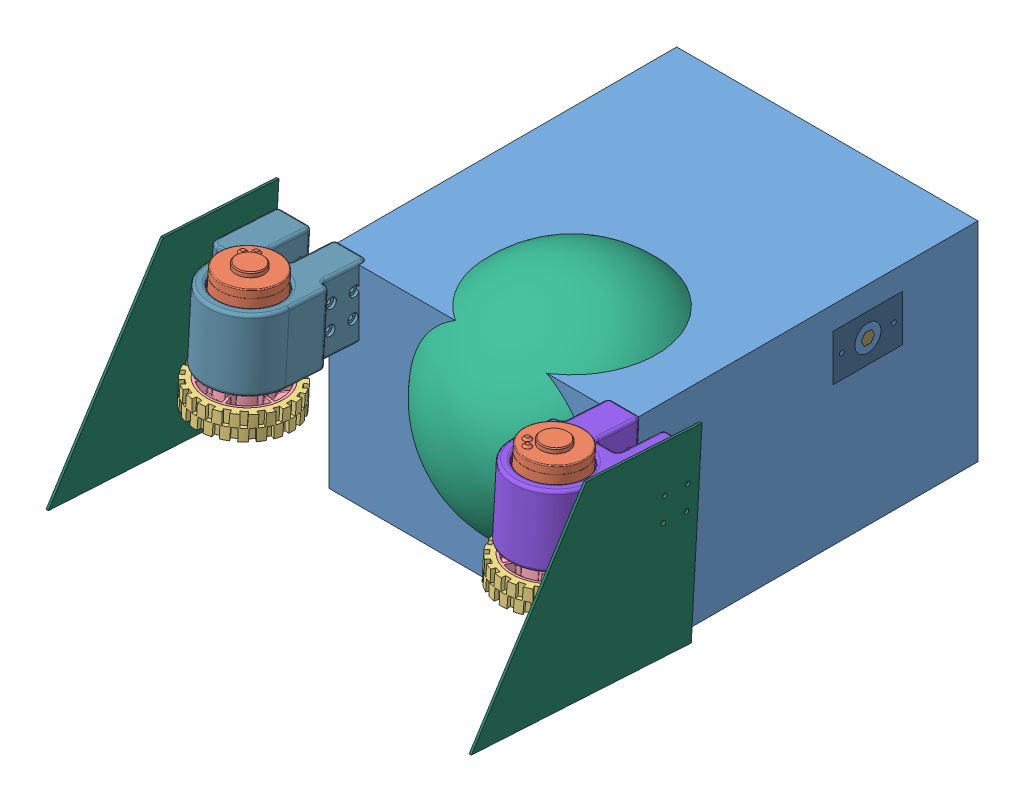
SolidWorks assembly shooter v2, configuration Default. Lengths in mm.
Overall size (466.79 413.55 625.13).
118 component instances, 42 part files, 85 mates.
Components (placement in the parent):
- shooter boundry-1: shooter boundry [Default] at origin size (330.2 228.6 381)
- MiniCIM Motor-1: MiniCIM Motor [Default] at (-2.032 166.4532 471.1566) x (0 0.998301 -0.058266) z (0 0.058266 0.998301) size (133.06 64.01 64.01)
- 4 in HiGrip Wheel-1: 4 in HiGrip Wheel [Default] at (1.2293 143.8954 473.9437) x (0 0.998301 -0.058266) z (-0.935788 0.020542 0.351965) size (35.12 101.6 101.6)
  - 4 in tread-1: 4 in tread [Default] at (-8.0517 2.5236 2.5343) size (25.4 101.6 101.6)
  - 4in 2013 Hub-1: 4in 2013 Hub [Default] at (-8.0517 2.5236 2.5343) size (35.12 82.55 82.55)
- am-0320a_8mm_Key_Hub-1: am-0320a_8mm_Key_Hub [Default] at (-2.032 158.6564 471.6117) x (0.162565 -0.05749 -0.985022) z (0 -0.998301 0.058266) size (57.15 57.15 25.4)
- am-0320a_8mm_Key_Hub-2: am-0320a_8mm_Key_Hub [Default] at (332.232 158.6564 471.6117) x (-0.795747 0.035287 0.6046) z (0 -0.998301 0.058266) size (57.15 57.15 25.4)
- 4 in HiGrip Wheel-2: 4 in HiGrip Wheel [Default] at (330.8694 143.6172 469.1771) x (0 0.998301 -0.058266) z (0.922364 0.022509 0.385666) size (35.12 101.6 101.6)
  - 4 in tread-1: 4 in tread [Default] at (-8.0517 2.5236 2.5343) size (25.4 101.6 101.6)
  - 4in 2013 Hub-1: 4in 2013 Hub [Default] at (-8.0517 2.5236 2.5343) size (35.12 82.55 82.55)
- MiniCIM Motor-2: MiniCIM Motor [Default] at (332.232 166.4532 471.1566) x (0 0.998301 -0.058266) z (1 0 0) size (133.06 64.01 64.01)
- ball-1: ball [Default] at (188.4903 141.6409 303.234) x (0.677862 -0.6998 0.22535) z (-0.733706 -0.663389 0.146935) size (254 254 254)
- shooter bar-1: shooter bar [Default] at (317.5 150.9632 96.7731) x (0 0.058266 0.998301) z (-1 0 0) size (330.2 50.8 4.06)
- shooter bar-2: shooter bar [Default] at (16.764 150.9632 96.7731) x (0 0.058266 0.998301) z (-1 0 0) size (330.2 50.8 4.06)
- CIM mount - right - 3d print-2: CIM mount - right - 3d print [Default] at (287.782 162.7039 515.9011) x (1 0 0) z (0 0.058266 0.998301) size (107.95 76.2 139.7)
- shooter cross bar-3: shooter cross bar [Default] at (16.764 2.522 169.0449) x (1 0 0) z (0 0.058266 0.998301) size (296.67 203.2 50.8)
- shooter cross bar-4: shooter cross bar [Default] at (16.764 9.9217 295.8291) x (1 0 0) z (0 0.058266 0.998301) size (296.67 203.2 50.8)
- bearing block-1: bearing block [Default] at (330.2 203.2 82.55) x (0 -1 0) z (-1 0 0) size (50.8 76.2 8.89)
- bearing block-2: bearing block [Default] at (0 152.4 82.55) x (0 1 0) z (1 0 0) size (50.8 76.2 8.89)
- .5in hex bearing-3: .5in hex bearing [Default] at (327.66 177.8 120.65) x (0 0.893687 0.448691) z (0 -0.448691 0.893687) size (31.72 7.92 31.72)
- .5in hex bearing-4: .5in hex bearing [Default] at (2.54 177.8 120.65) x (0 -0.893687 -0.448691) z (0 -0.448691 0.893687) size (31.72 7.92 31.72)
- shaft-2: shaft [Default] at (330.2 177.8 120.65) x (0 0.835421 -0.54961) z (-1 0 0) size (14.66 12.7 330.2)
- s35-15he-500h-1: s35-15he-500h [Default] at (283.972 177.8 120.65) x (0 -0.058266 -0.998301) z (-1 0 0) size (50.14 50.4 10.29)
- CIM mount - left - 3d print-1: CIM mount - left - 3d print [Default] at (42.418 162.7039 515.9011) x (1 0 0) z (0 0.058266 0.998301) size (107.95 76.2 139.7)
- gate lifter-1: gate lifter [Default] at (395.732 67.1962 623.2482) x (0 -0.058266 -0.998301) z (1 0 0) size (241.3 203.2 2.54)
- gate lifter-2: gate lifter [Default] at (-68.072 67.1962 623.2482) x (0 -0.058266 -0.998301) z (1 0 0) size (241.3 203.2 2.54)
- bottom bar-1: bottom bar [Default] at (190.5 8.8245 346.7796) x (0 -0.058266 -0.998301) z (1 0 0) size (177.8 4.06 50.8)
- VEXpro-VersaPlanetary-2stage-with-BAG-1: VEXpro-VersaPlanetary-2stage-with-BAG [Default] at (215.175 106 33.7) x (0 0 1) z (-1 0 0) size (49.3 49.3 173.58)
  - 217-2625-001 Rev1-1: 217-2625-001 Rev1 [Default] at origin size (42 42 18)
  - 217-2625-002 Rev1-1: 217-2625-002 Rev1 [Default] at (0 0 -29.4) size (42 42 17.13)
  - 217-2625-003 Rev1-1: 217-2625-003 Rev1 [Default] at (0 0 -43.6478) x (0.966651 -0.256095 0) z (0 0 -1) size (17 17 64.12)
  - 217-2625-009 Rev1-1: 217-2625-009 Rev1 [Default] at (0 0 -3.48) x (-0.609619 0.792694 0) z (0 0 -1) size (18 18 13)
  - 217-2625-100-1: 217-2625-100 [Default] at (0 0 -18.8454) x (0.784104 -0.62063 0) z (0 0 1) size (39.26 38.9 12.7)
    - 217-2625-008 Rev1-1: 217-2625-008 Rev1 [Default] at origin size (34.7 34.7 4.7)
    - 217-2625-010 Rev1-1: 217-2625-010 Rev1 [Default] at (0 10.193 3.65) x (0.999813 0.019336 0) z (0 0 1) size (4 4 12)
    - 217-2625-010 Rev1-2: 217-2625-010 Rev1 [Default] at (8.691 -5.3258 3.65) size (4 4 12)
    - 217-2625-010 Rev1-3: 217-2625-010 Rev1 [Default] at (-8.691 -5.3258 3.65) size (4 4 12)
    - 217-2625-005 Rev1_Planet_Revolving_Follower01-1: 217-2625-005 Rev1_Planet_Revolving_Follower01 [Default] at (8.691 -5.3258 6.35) x (0.932816 0.360354 0) z (0 0 1) size (16.91 16.92 8)
    - 217-2625-005 Rev1_Planet_Revolving_Follower01-2: 217-2625-005 Rev1_Planet_Revolving_Follower01 [Default] at (-8.691 -5.3258 6.35) x (-0.932788 -0.360426 0) z (0 0 1) size (16.91 16.92 8)
    - 217-2625-005 Rev1_Planet_Revolving_Follower01-3: 217-2625-005 Rev1_Planet_Revolving_Follower01 [Default] at (0 10.193 6.35) x (0.893583 0.448898 0) z (0 0 1) size (16.91 16.92 8)
  - 217-2625-007 Rev1_Sun_Driver01-1: 217-2625-007 Rev1_Sun_Driver01 [Default] at (0 0 -11.5575) x (0.564419 -0.825488 0) z (0 0 1) size (14.49 14.49 12.72)
  - 217-2742-1: 217-2742 [Default] at (0 0 -51.4002) x (0 0 1) z (-0.997393 0.072165 0) size (7 28 28)
  - 217-2742-2: 217-2742 [Default] at (0 0 -43.1002) x (0 0 1) z (-1 0 0) size (7 28 28)
  - 217-2741-1: 217-2741 [Default] at (0 0 -7) x (0 0 1) z (-0.951311 0.308231 0) size (5 26 26)
  - TRUARC-MSH-15_98541A410-1: TRUARC-MSH-15_98541A410 [Default] at (0 0 -35.4954) x (0 0 -1) z (0.980859 -0.194721 0) size (1 19.6 17.4)
  - SPRGW0856-1102-012_9714K62-1: SPRGW0856-1102-012_9714K62 [Default] at (0 0 -44.1002) x (-0.695225 0.718792 0) z (-0.718792 -0.695225 0) size (29.09 5.11 30.79)
  - SSS1032-0125ZB_94105A824-1: SSS1032-0125ZB_94105A824 [Default] at (5.4759 4.2112 1.995) x (-0.605001 0.78669 -0.122849) z (0.792694 0.609619 0) size (4.83 4.84 3.3)
  - TRUARC-5103-68_97414A675_grv-1: TRUARC-5103-68_97414A675_grv [Default] at (1.1965 0.0349 -1.3834) x (0 0 -1) z (-0.029125 0.999576 0) size (1.07 15.49 20.19)
  - 217-3351-1: 217-3351 [Default] at (0 0 10.675) x (0 -1 0) z (0 0 -1) size (40.4 40.4 81.5)
  - 217-2816-001 Rev1-1: 217-2816-001 Rev1 [Default] at (0 0 -29.55) x (1 0 0) z (0 0 -1) size (42 42 14.5)
  - SSA_SSA0832-1750ZC-1: SSA_SSA0832-1750ZC [Default] at (-17.5 17.5 -47.261) x (-0.769034 -0.639207 0) z (0.639207 -0.769034 0) size (6.73 48.51 6.73)
  - SSA_SSA0832-1750ZC-2: SSA_SSA0832-1750ZC [Default] at (17.5 -17.5 -47.261) x (0.162252 0.986749 0) z (-0.986749 0.162252 0) size (6.73 48.51 6.73)
  - 217-2625-011 Rev1-1: 217-2625-011 Rev1 [Default] at (0 0 1.37) x (-0.792694 -0.609619 0) z (-0.609619 0.792694 0) size (8.01 7.5 7.94)
  - SSA_SSA0832-0500ZC-1: SSA_SSA0832-0500ZC [Default] at (-17.5 17.5 10.675) x (0.592766 0.805375 0) z (0.805375 -0.592766 0) size (6.73 16.76 6.73)
  - SSA_SSA0832-0500ZC-2: SSA_SSA0832-0500ZC [Default] at (17.5 -17.5 10.675) x (-0.592766 -0.805375 0) z (-0.805375 0.592766 0) size (6.73 16.76 6.73)
  - SSHCM004_SSHCM004070010C-1: SSHCM004_SSHCM004070010C [Default] at (0 -12.5 7.5) x (-0.451598 -0.892221 0) z (0.892221 -0.451598 0) size (7 14 7)
  - SSHCM004_SSHCM004070010C-2: SSHCM004_SSHCM004070010C [Default] at (0 12.5 7.5) x (-0.447517 -0.894275 0) z (0.894275 -0.447517 0) size (7 14 7)
  - 217-2816-001 Rev1-2: 217-2816-001 Rev1 [Default] at (0 0 -16.85) x (1 0 0) z (0 0 -1) size (42 42 14.5)
  - 217-2818 Rev1-1: 217-2818 Rev1 [Default] at (0 0 -31.5454) size (49.07 49.07 17.4)
    - 217-2725-001 Rev1_24t Sun-1: 217-2725-001 Rev1_24t Sun [Default] at (0 0 8.7) size (14.45 14.45 12.7)
    - 217-2725-002 Rev1_24t Planet-1: 217-2725-002 Rev1_24t Planet [Default] at (-12.089 0 6.35) x (-0.130526 0.991445 0) z (0 0 -1) size (13.17 13.15 8)
    - 217-2724-002 Rev1-1: 217-2724-002 Rev1 [Default] x (0.707107 -0.707107 0) z (0 0 -1) size (34.7 34.7 4.7)
    - 217-2625-010 Rev1-1: 217-2625-010 Rev1 [Default] at (-12.089 0 3.65) x (0.971612 -0.236582 0) z (0 0 1) size (4 4 12)
    - 217-2725-002 Rev1_24t Planet-2: 217-2725-002 Rev1_24t Planet [Default] at (0 -12.089 6.35) x (-0.991445 -0.130526 0) z (0 0 -1) size (13.17 13.15 8)
    - 217-2725-002 Rev1_24t Planet-3: 217-2725-002 Rev1_24t Planet [Default] at (12.089 0 6.35) x (0.130526 -0.991445 0) z (0 0 -1) size (13.17 13.15 8)
    - 217-2725-002 Rev1_24t Planet-4: 217-2725-002 Rev1_24t Planet [Default] at (0 12.089 6.35) x (0.991445 0.130526 0) z (0 0 -1) size (13.17 13.15 8)
    - 217-2625-010 Rev1-2: 217-2625-010 Rev1 [Default] at (0 -12.089 3.65) x (0.236582 0.971612 0) z (0 0 1) size (4 4 12)
    - 217-2625-010 Rev1-3: 217-2625-010 Rev1 [Default] at (12.089 0 3.65) x (-0.971612 0.236582 0) z (0 0 1) size (4 4 12)
    - 217-2625-010 Rev1-4: 217-2625-010 Rev1 [Default] at (0 12.089 3.65) x (-0.236582 -0.971612 0) z (0 0 1) size (4 4 12)
  - 217-2822-003 Rev4-1: 217-2822-003 Rev4 [Default] at (0 0 9) x (0 -1 0) z (0 0 1) size (42 42 4.8)
- s35-15he-500h-2: s35-15he-500h [Default] at (283.972 106 33.7) x (0 0.650581 -0.759437) z (-1 0 0) size (50.14 50.4 10.29)
- .5in hex bearing-5: .5in hex bearing [Default] at (169.418 177.8 120.65) x (0 -0.058266 -0.998301) z (0 0.998301 -0.058266) size (31.72 7.92 31.72)
- kicker-1: kicker [Default] at (163.068 29.698 127.0959) x (0 0.12834 -0.99173) z (1 0 0) size (50.8 177.8 4.06)
- VEXpro-VersaPlanetary-2stage-with-BAG-2: VEXpro-VersaPlanetary-2stage-with-BAG [Default] at (107.225 169.5 33.7) x (0 0 1) z (-1 0 0) size (49.3 49.3 173.58)
  - 217-2625-001 Rev1-1: 217-2625-001 Rev1 [Default] at origin size (42 42 18)
  - 217-2625-002 Rev1-1: 217-2625-002 Rev1 [Default] at (0 0 -29.4) size (42 42 17.13)
  - 217-2625-003 Rev1-1: 217-2625-003 Rev1 [Default] at (0 0 -43.6478) x (0.966651 -0.256095 0) z (0 0 -1) size (17 17 64.12)
  - 217-2625-009 Rev1-1: 217-2625-009 Rev1 [Default] at (0 0 -3.48) x (-0.609619 0.792694 0) z (0 0 -1) size (18 18 13)
  - 217-2625-100-1: 217-2625-100 [Default] at (0 0 -18.8454) x (0.784104 -0.62063 0) z (0 0 1) size (39.26 38.9 12.7)
    - 217-2625-008 Rev1-1: 217-2625-008 Rev1 [Default] at origin size (34.7 34.7 4.7)
    - 217-2625-010 Rev1-1: 217-2625-010 Rev1 [Default] at (0 10.193 3.65) x (0.999813 0.019336 0) z (0 0 1) size (4 4 12)
    - 217-2625-010 Rev1-2: 217-2625-010 Rev1 [Default] at (8.691 -5.3258 3.65) size (4 4 12)
    - 217-2625-010 Rev1-3: 217-2625-010 Rev1 [Default] at (-8.691 -5.3258 3.65) size (4 4 12)
    - 217-2625-005 Rev1_Planet_Revolving_Follower01-1: 217-2625-005 Rev1_Planet_Revolving_Follower01 [Default] at (8.691 -5.3258 6.35) x (0.932816 0.360354 0) z (0 0 1) size (16.91 16.92 8)
    - 217-2625-005 Rev1_Planet_Revolving_Follower01-2: 217-2625-005 Rev1_Planet_Revolving_Follower01 [Default] at (-8.691 -5.3258 6.35) x (-0.932788 -0.360426 0) z (0 0 1) size (16.91 16.92 8)
    - 217-2625-005 Rev1_Planet_Revolving_Follower01-3: 217-2625-005 Rev1_Planet_Revolving_Follower01 [Default] at (0 10.193 6.35) x (0.893583 0.448898 0) z (0 0 1) size (16.91 16.92 8)
  - 217-2625-007 Rev1_Sun_Driver01-1: 217-2625-007 Rev1_Sun_Driver01 [Default] at (0 0 -11.5575) x (0.564419 -0.825488 0) z (0 0 1) size (14.49 14.49 12.72)
  - 217-2742-1: 217-2742 [Default] at (0 0 -51.4002) x (0 0 1) z (-0.997393 0.072165 0) size (7 28 28)
  - 217-2742-2: 217-2742 [Default] at (0 0 -43.1002) x (0 0 1) z (-1 0 0) size (7 28 28)
  - 217-2741-1: 217-2741 [Default] at (0 0 -7) x (0 0 1) z (-0.951311 0.308231 0) size (5 26 26)
  - TRUARC-MSH-15_98541A410-1: TRUARC-MSH-15_98541A410 [Default] at (0 0 -35.4954) x (0 0 -1) z (0.980859 -0.194721 0) size (1 19.6 17.4)
  - SPRGW0856-1102-012_9714K62-1: SPRGW0856-1102-012_9714K62 [Default] at (0 0 -44.1002) x (-0.695225 0.718792 0) z (-0.718792 -0.695225 0) size (29.09 5.11 30.79)
  - SSS1032-0125ZB_94105A824-1: SSS1032-0125ZB_94105A824 [Default] at (5.4759 4.2112 1.995) x (-0.605001 0.78669 -0.122849) z (0.792694 0.609619 0) size (4.83 4.84 3.3)
  - TRUARC-5103-68_97414A675_grv-1: TRUARC-5103-68_97414A675_grv [Default] at (1.1965 0.0349 -1.3834) x (0 0 -1) z (-0.029125 0.999576 0) size (1.07 15.49 20.19)
  - 217-3351-1: 217-3351 [Default] at (0 0 10.675) x (0 -1 0) z (0 0 -1) size (40.4 40.4 81.5)
  - 217-2816-001 Rev1-1: 217-2816-001 Rev1 [Default] at (0 0 -29.55) x (1 0 0) z (0 0 -1) size (42 42 14.5)
  - SSA_SSA0832-1750ZC-1: SSA_SSA0832-1750ZC [Default] at (-17.5 17.5 -47.261) x (-0.769034 -0.639207 0) z (0.639207 -0.769034 0) size (6.73 48.51 6.73)
  - SSA_SSA0832-1750ZC-2: SSA_SSA0832-1750ZC [Default] at (17.5 -17.5 -47.261) x (0.162252 0.986749 0) z (-0.986749 0.162252 0) size (6.73 48.51 6.73)
  - 217-2625-011 Rev1-1: 217-2625-011 Rev1 [Default] at (0 0 1.37) x (-0.792694 -0.609619 0) z (-0.609619 0.792694 0) size (8.01 7.5 7.94)
  - SSA_SSA0832-0500ZC-1: SSA_SSA0832-0500ZC [Default] at (-17.5 17.5 10.675) x (0.592766 0.805375 0) z (0.805375 -0.592766 0) size (6.73 16.76 6.73)
  - SSA_SSA0832-0500ZC-2: SSA_SSA0832-0500ZC [Default] at (17.5 -17.5 10.675) x (-0.592766 -0.805375 0) z (-0.805375 0.592766 0) size (6.73 16.76 6.73)
  - SSHCM004_SSHCM004070010C-1: SSHCM004_SSHCM004070010C [Default] at (0 -12.5 7.5) x (-0.451598 -0.892221 0) z (0.892221 -0.451598 0) size (7 14 7)
  - SSHCM004_SSHCM004070010C-2: SSHCM004_SSHCM004070010C [Default] at (0 12.5 7.5) x (-0.447517 -0.894275 0) z (0.894275 -0.447517 0) size (7 14 7)
  - 217-2816-001 Rev1-2: 217-2816-001 Rev1 [Default] at (0 0 -16.85) x (1 0 0) z (0 0 -1) size (42 42 14.5)
  - 217-2818 Rev1-1: 217-2818 Rev1 [Default] at (0 0 -31.5454) size (49.07 49.07 17.4)
    - 217-2725-001 Rev1_24t Sun-1: 217-2725-001 Rev1_24t Sun [Default] at (0 0 8.7) size (14.45 14.45 12.7)
    - 217-2725-002 Rev1_24t Planet-1: 217-2725-002 Rev1_24t Planet [Default] at (-12.089 0 6.35) x (-0.130526 0.991445 0) z (0 0 -1) size (13.17 13.15 8)
    - 217-2724-002 Rev1-1: 217-2724-002 Rev1 [Default] x (0.707107 -0.707107 0) z (0 0 -1) size (34.7 34.7 4.7)
    - 217-2625-010 Rev1-1: 217-2625-010 Rev1 [Default] at (-12.089 0 3.65) x (0.971612 -0.236582 0) z (0 0 1) size (4 4 12)
    - 217-2725-002 Rev1_24t Planet-2: 217-2725-002 Rev1_24t Planet [Default] at (0 -12.089 6.35) x (-0.991445 -0.130526 0) z (0 0 -1) size (13.17 13.15 8)
    - 217-2725-002 Rev1_24t Planet-3: 217-2725-002 Rev1_24t Planet [Default] at (12.089 0 6.35) x (0.130526 -0.991445 0) z (0 0 -1) size (13.17 13.15 8)
    - 217-2725-002 Rev1_24t Planet-4: 217-2725-002 Rev1_24t Planet [Default] at (0 12.089 6.35) x (0.991445 0.130526 0) z (0 0 -1) size (13.17 13.15 8)
    - 217-2625-010 Rev1-2: 217-2625-010 Rev1 [Default] at (0 -12.089 3.65) x (0.236582 0.971612 0) z (0 0 1) size (4 4 12)
    - 217-2625-010 Rev1-3: 217-2625-010 Rev1 [Default] at (12.089 0 3.65) x (-0.971612 0.236582 0) z (0 0 1) size (4 4 12)
    - 217-2625-010 Rev1-4: 217-2625-010 Rev1 [Default] at (0 12.089 3.65) x (-0.236582 -0.971612 0) z (0 0 1) size (4 4 12)
  - 217-2822-003 Rev4-1: 217-2822-003 Rev4 [Default] at (0 0 9) x (0 -1 0) z (0 0 1) size (42 42 4.8)
- s35-15he-500h-3: s35-15he-500h [Default] at (179.832 169.5 33.7) x (0 0.323435 -0.94625) z (-1 0 0) size (50.14 50.4 10.29)
- am-0737-1: am-0737 [Default] at (181.864 177.8 120.65) x (0 0.794694 0.607011) z (-1 0 0) size (71.96 71.42 4.06)
Mates (geometry in assembly coordinates):
- Concentric1: concentric aligned: cylinder of 4 in HiGrip Wheel-1/4in 2013 Hub-1 through (-2.032 146.2316 472.3368) axis (0 0.998301 -0.058266) radius 14.2875; cylinder of am-0320a_8mm_Key_Hub-1 through (-2.032 133.2996 473.0916) axis (0 0.998301 -0.058266) radius 12.1412
- Coincident3: coincident anti-aligned: plane of 4 in HiGrip Wheel-1/4in 2013 Hub-1 through (-2.032 153.2047 471.9298) normal (0 0.998301 -0.058266); plane of am-0320a_8mm_Key_Hub-1 through (-12.1388 156.779 533.1699) normal (0 -0.998301 0.058266)
- Concentric2: concentric anti-aligned: cylinder of 4 in HiGrip Wheel-1/4in 2013 Hub-1 through (-10.4274 117.0407 451.7192) axis (0 0.998301 -0.058266) radius 2.159; cylinder of am-0320a_8mm_Key_Hub-1 through (-10.4274 157.3581 449.3661) axis (0 -0.998301 0.058266) radius 2.5908
- Concentric3: concentric anti-aligned: cylinder of MiniCIM Motor-1 through (-2.032 130.9136 473.2308) axis (0 0.998301 -0.058266) radius 4; cylinder of am-0320a_8mm_Key_Hub-1 through (-2.032 158.6564 471.6117) axis (0 -0.998301 0.058266) radius 4.0259
- Distance1: distance = 3.81 mm anti-aligned: plane of am-0320a_8mm_Key_Hub-1 through (-2.032 158.6564 471.6117) normal (0 0.998301 -0.058266); plane of MiniCIM Motor-1 through (-2.032 162.46 471.3897) normal (0 -0.998301 0.058266)
- Concentric4: concentric aligned: cylinder of am-0320a_8mm_Key_Hub-2 through (332.232 133.2996 473.0916) axis (0 0.998301 -0.058266) radius 12.1412; cylinder of 4 in HiGrip Wheel-2/4in 2013 Hub-1 through (332.232 146.2316 472.3368) axis (0 0.998301 -0.058266) radius 14.2875
- Coincident5: coincident anti-aligned: plane of am-0320a_8mm_Key_Hub-2 through (381.7046 151.0109 434.3411) normal (0 -0.998301 0.058266); plane of 4 in HiGrip Wheel-2/4in 2013 Hub-1 through (332.232 153.2047 471.9298) normal (0 0.998301 -0.058266)
- Concentric5: concentric anti-aligned: cylinder of am-0320a_8mm_Key_Hub-2 through (308.6112 158.8321 474.6216) axis (0 -0.998301 0.058266) radius 2.5908; cylinder of 4 in HiGrip Wheel-2/4in 2013 Hub-1 through (308.6112 118.5147 476.9747) axis (0 0.998301 -0.058266) radius 2.159
- Concentric6: concentric anti-aligned: cylinder of am-0320a_8mm_Key_Hub-2 through (332.232 158.6564 471.6117) axis (0 -0.998301 0.058266) radius 4.0259; cylinder of MiniCIM Motor-2 through (332.232 130.9136 473.2308) axis (0 0.998301 -0.058266) radius 4
- Distance2: distance = 3.81 mm anti-aligned: plane of am-0320a_8mm_Key_Hub-2 through (332.232 158.6564 471.6117) normal (0 0.998301 -0.058266); plane of MiniCIM Motor-2 through (332.232 162.46 471.3897) normal (0 -0.998301 0.058266)
- Coincident7: coincident aligned: plane of MiniCIM Motor-1 through (-2.032 166.4532 471.1566) normal (0 -0.998301 0.058266); plane of MiniCIM Motor-2 through (332.232 166.4532 471.1566) normal (0 -0.998301 0.058266)
- Distance5: distance = 304.8 mm anti-aligned: plane of shooter bar-1 through (317.5 150.9632 96.7731) normal (1 0 0); plane of shooter bar-2 through (12.7 150.9632 96.7731) normal (-1 0 0)
- Width1: width anti-aligned: plane of shooter boundry-1 through (0 0 381) normal (-1 0 0); plane of shooter boundry-1 through (330.2 0 381) normal (1 0 0); plane of shooter bar-1 through (317.5 150.9632 96.7731) normal (1 0 0); plane of shooter bar-2 through (12.7 150.9632 96.7731) normal (-1 0 0)
- Concentric24: concentric aligned: cylinder of MiniCIM Motor-2 through (332.232 174.6688 470.6771) axis (0 0.998301 -0.058266) radius 32.004; cylinder of CIM mount - right - 3d print-2 through (332.232 66.878 476.9683) axis (0 0.998301 -0.058266) radius 33.02
- Concentric25: concentric anti-aligned: cylinder of MiniCIM Motor-2 through (332.232 164.9732 445.7997) axis (0 -0.998301 0.058266) radius 2.0193; cylinder of CIM mount - right - 3d print-2 through (332.232 164.9732 445.7997) axis (0 0.998301 -0.058266) radius 2.5527
- Coincident23: coincident anti-aligned: plane of MiniCIM Motor-2 through (332.232 166.4532 471.1566) normal (0 -0.998301 0.058266); plane of CIM mount - right - 3d print-2 through (287.782 169.0431 515.5311) normal (0 0.998301 -0.058266)
- Concentric28: concentric anti-aligned: cylinder of shooter bar-2 through (12.7 193.4383 170.6237) axis (-1 0 0) radius 2.5527; cylinder of shooter cross bar-3 through (20.828 193.4383 170.6237) axis (1 0 0) radius 2.5527
- Concentric29: concentric anti-aligned: cylinder of shooter bar-2 through (12.7 169.5614 197.4605) axis (-1 0 0) radius 2.5527; cylinder of shooter cross bar-3 through (20.828 169.5614 197.4605) axis (1 0 0) radius 2.5527
- Coincident25: coincident anti-aligned: plane of shooter bar-2 through (16.764 150.9632 96.7731) normal (1 0 0); plane of shooter cross bar-3 through (16.764 208.3367 207.919) normal (-1 0 0)
- Concentric30: concentric aligned: cylinder of shooter bar-1 through (313.436 193.4383 170.6237) axis (-1 0 0) radius 2.5527; cylinder of shooter cross bar-3 through (309.372 193.4383 170.6237) axis (-1 0 0) radius 2.5527
- Concentric31: concentric anti-aligned: cylinder of shooter bar-2 through (12.7 176.9611 324.2448) axis (-1 0 0) radius 2.5527; cylinder of shooter cross bar-4 through (20.828 176.9611 324.2448) axis (1 0 0) radius 2.5527
- Concentric32: concentric anti-aligned: cylinder of shooter bar-2 through (12.7 200.838 297.408) axis (-1 0 0) radius 2.5527; cylinder of shooter cross bar-4 through (20.828 200.838 297.408) axis (1 0 0) radius 2.5527
- Coincident26: coincident anti-aligned: plane of shooter bar-2 through (16.764 150.9632 96.7731) normal (1 0 0); plane of shooter cross bar-4 through (16.764 215.7364 334.7033) normal (-1 0 0)
- Tangent6: tangent anti-aligned: sphere of ball-1; plane of shooter cross bar-4 through (107.3474 16.9387 346.306) normal (0 0.998301 -0.058266)
- Coincident32: coincident aligned: plane of shooter boundry-1 through (330.2 0 381) normal (1 0 0); plane of bearing block-1 through (330.2 203.2 82.55) normal (1 0 0)
- Coincident36: coincident anti-aligned: plane of shooter bar-1 through (317.5 150.9632 96.7731) normal (1 0 0); plane of CIM mount - right - 3d print-2 through (317.5 219.2241 372.6645) normal (-1 0 0)
- Coincident39: coincident anti-aligned: plane of bearing block-1 through (321.31 203.2 82.55) normal (-1 0 0); plane of .5in hex bearing-3 through (321.31 177.8 120.65) normal (1 0 0)
- Concentric34: concentric aligned: cylinder of bearing block-1 through (321.31 177.8 120.65) axis (1 0 0) radius 14.2875; cylinder of .5in hex bearing-3 through (319.7352 177.8 120.65) axis (1 0 0) radius 14.2875
- Coincident46: coincident aligned: plane of bearing block-1 through (330.2 203.2 82.55) normal (1 0 0); plane of shaft-2 through (330.2 177.8 120.65) normal (1 0 0)
- Coincident47: coincident anti-aligned: plane of .5in hex bearing-3 through (319.7352 177.3728 113.3301) normal (0 0.54961 0.835421); plane of shaft-2 through (0 177.3728 113.3301) normal (0 -0.54961 -0.835421)
- Coincident48: coincident anti-aligned: plane of .5in hex bearing-4 through (10.4648 171.2472 117.36) normal (0 0.54961 0.835421); plane of shaft-2 through (0 177.3728 113.3301) normal (0 -0.54961 -0.835421)
- Coincident49: coincident anti-aligned: plane of .5in hex bearing-4 through (10.4648 171.6744 124.6799) normal (0 0.998301 -0.058266); plane of shaft-2 through (0 171.2472 117.36) normal (0 -0.998301 0.058266)
- Coincident53: coincident anti-aligned: plane of shooter bar-1 through (317.5 171.2472 117.36) normal (0 0.998301 -0.058266); plane of shaft-2 through (0 171.2472 117.36) normal (0 -0.998301 0.058266)
- Coincident54: coincident anti-aligned: plane of shooter bar-2 through (16.764 171.2472 117.36) normal (0 0.998301 -0.058266); plane of shaft-2 through (0 171.2472 117.36) normal (0 -0.998301 0.058266)
- Coincident55: coincident anti-aligned: plane of shooter bar-2 through (16.764 171.6744 124.6799) normal (0 0.448691 -0.893687); plane of shaft-2 through (0 171.6744 124.6799) normal (0 -0.448691 0.893687)
- Coincident59: coincident aligned: plane of shooter boundry-1 through (0 0 381) normal (-1 0 0); plane of bearing block-2 through (0 152.4 82.55) normal (-1 0 0)
- Coincident60: coincident aligned: plane of bearing block-1 through (321.31 203.2 158.75) normal (0 0 1); plane of bearing block-2 through (8.89 152.4 158.75) normal (0 0 1)
- Coincident61: coincident anti-aligned: plane of bearing block-2 through (8.89 152.4 82.55) normal (1 0 0); plane of .5in hex bearing-4 through (8.89 177.8 120.65) normal (-1 0 0)
- Concentric35: concentric aligned: cylinder of bearing block-2 through (8.89 177.8 120.65) axis (-1 0 0) radius 14.2875; cylinder of .5in hex bearing-4 through (10.4648 177.8 120.65) axis (-1 0 0) radius 14.2875
- Coincident65: coincident anti-aligned: plane of shaft-2 through (0 184.3528 123.94) normal (0 0.998301 -0.058266); plane of s35-15he-500h-1 through (288.036 184.3528 123.94) normal (0 -0.998301 0.058266)
- Coincident66: coincident anti-aligned: plane of shaft-2 through (0 183.9256 116.6201) normal (0 0.448691 -0.893687); plane of s35-15he-500h-1 through (288.036 179.5085 114.4024) normal (0 -0.448691 0.893687)
- Distance10: distance = 25.4 mm anti-aligned: plane of s35-15he-500h-1 through (288.036 177.8 120.65) normal (1 0 0); plane of shooter bar-1 through (313.436 150.9632 96.7731) normal (-1 0 0)
- Coincident68: coincident anti-aligned: plane of shooter bar-1 through (317.5 150.9632 96.7731) normal (1 0 0); plane of CIM mount - right - 3d print-2 through (317.5 219.2241 372.6645) normal (-1 0 0)
- Concentric36: concentric aligned: cylinder of shooter bar-1 through (313.436 180.661 387.6369) axis (-1 0 0) radius 2.5527; cylinder of CIM mount - right - 3d print-2 through (297.307 180.661 387.6369) axis (-1 0 0) radius 2.5527
- Concentric37: concentric aligned: cylinder of shooter bar-1 through (313.436 207.4978 411.5138) axis (-1 0 0) radius 2.5527; cylinder of CIM mount - right - 3d print-2 through (297.307 207.4978 411.5138) axis (-1 0 0) radius 2.5527
- Concentric38: concentric anti-aligned: cylinder of MiniCIM Motor-1 through (-27.432 166.4532 471.1566) axis (0 -0.998301 0.058266) radius 2.0193; cylinder of CIM mount - left - 3d print-1 through (-27.432 166.4532 471.1566) axis (0 0.998301 -0.058266) radius 2.5527
- Concentric39: concentric aligned: cylinder of MiniCIM Motor-1 through (-2.032 174.6688 470.6771) axis (0 0.998301 -0.058266) radius 32.004; cylinder of CIM mount - left - 3d print-1 through (-2.032 66.878 476.9683) axis (0 0.998301 -0.058266) radius 33.02
- Coincident69: coincident anti-aligned: plane of shooter bar-2 through (12.7 150.9632 96.7731) normal (-1 0 0); plane of CIM mount - left - 3d print-1 through (12.7 219.2241 372.6645) normal (1 0 0)
- Concentric40: concentric anti-aligned: cylinder of shooter bar-2 through (12.7 206.0178 386.1569) axis (-1 0 0) radius 2.5527; cylinder of CIM mount - left - 3d print-1 through (32.893 206.0178 386.1569) axis (1 0 0) radius 2.5527
- Concentric41: concentric anti-aligned: cylinder of shooter bar-2 through (12.7 182.1409 412.9937) axis (-1 0 0) radius 2.5527; cylinder of CIM mount - left - 3d print-1 through (32.893 182.1409 412.9937) axis (1 0 0) radius 2.5527
- Coincident71: coincident anti-aligned: plane of CIM mount - right - 3d print-2 through (395.732 162.7039 515.9011) normal (1 0 0); plane of gate lifter-1 through (395.732 67.1962 623.2482) normal (-1 0 0)
- Concentric42: concentric aligned: cylinder of CIM mount - right - 3d print-2 through (395.732 206.0178 386.1569) axis (1 0 0) radius 2.5527; cylinder of gate lifter-1 through (398.272 206.0178 386.1569) axis (1 0 0) radius 2.5527
- Concentric43: concentric aligned: cylinder of CIM mount - right - 3d print-2 through (395.732 182.1409 412.9937) axis (1 0 0) radius 2.5527; cylinder of gate lifter-1 through (398.272 182.1409 412.9937) axis (1 0 0) radius 2.5527
- Coincident72: coincident anti-aligned: plane of CIM mount - left - 3d print-1 through (-65.532 162.7039 515.9011) normal (-1 0 0); plane of gate lifter-2 through (-65.532 67.1962 623.2482) normal (1 0 0)
- Concentric44: concentric anti-aligned: cylinder of CIM mount - left - 3d print-1 through (-65.532 206.0178 386.1569) axis (-1 0 0) radius 2.5527; cylinder of gate lifter-2 through (-65.532 206.0178 386.1569) axis (1 0 0) radius 2.5527
- Concentric45: concentric anti-aligned: cylinder of CIM mount - left - 3d print-1 through (-65.532 182.1409 412.9937) axis (-1 0 0) radius 2.5527; cylinder of gate lifter-2 through (-65.532 182.1409 412.9937) axis (1 0 0) radius 2.5527
- Coincident74: coincident anti-aligned: plane of shooter cross bar-4 through (105.664 12.8816 346.5428) normal (0 -0.998301 0.058266); plane of bottom bar-1 through (190.5 12.8816 346.5428) normal (0 0.998301 -0.058266)
- Coincident75: coincident aligned: plane of shooter cross bar-4 through (16.764 12.8816 346.5428) normal (0 0.058266 0.998301); plane of bottom bar-1 through (190.5 12.8816 346.5428) normal (0 0.058266 0.998301)
- Concentric46: concentric aligned: cylinder of shooter cross bar-4 through (152.4 14.7188 308.2708) axis (0 0.998301 -0.058266) radius 1.5875; cylinder of bottom bar-1 through (152.4 10.6617 308.5075) axis (0 0.998301 -0.058266) radius 1.5875
- Concentric47: concentric aligned: cylinder of shooter cross bar-4 through (177.8 16.1987 333.6276) axis (0 0.998301 -0.058266) radius 1.5875; cylinder of bottom bar-1 through (177.8 12.1416 333.8644) axis (0 0.998301 -0.058266) radius 1.5875
- Concentric48: concentric aligned: cylinder of shooter cross bar-3 through (177.8 7.319 181.4865) axis (0 0.998301 -0.058266) radius 1.5875; cylinder of bottom bar-1 through (177.8 3.2619 181.7233) axis (0 0.998301 -0.058266) radius 1.5875
- Concentric49: concentric aligned: cylinder of shooter cross bar-3 through (152.4 8.799 206.8434) axis (0 0.998301 -0.058266) radius 1.5875; cylinder of bottom bar-1 through (152.4 4.7419 207.0802) axis (0 0.998301 -0.058266) radius 1.5875
- Distance13: distance = 12.7 mm aligned: plane of shooter boundry-1 through (0 0 0) normal (0 0 -1); plane of VEXpro-VersaPlanetary-2stage-with-BAG-1/217-2625-002 Rev1-1 through (266.7 85 12.7) normal (0 0 -1)
- Distance11: distance = 101.6 mm aligned: plane of VEXpro-VersaPlanetary-2stage-with-BAG-1/217-2625-001 Rev1-1 through (219.175 127 12.7) normal (0 1 0); plane of shooter boundry-1 through (0 228.6 381) normal (0 1 0)
- Distance12: distance = 63.5 mm aligned: plane of VEXpro-VersaPlanetary-2stage-with-BAG-1/217-2625-002 Rev1-1 through (266.7 127 12.7) normal (1 0 0); plane of shooter boundry-1 through (330.2 0 381) normal (1 0 0)
- Coincident80: coincident aligned: plane of s35-15he-500h-1 through (288.036 177.8 120.65) normal (1 0 0); plane of s35-15he-500h-2 through (288.036 106 33.7) normal (1 0 0)
- GearMate1: gear = 5.1816 : 5.1816 mm: cylinder of s35-15he-500h-2 through (288.036 128.2814 28.3858) axis (1 0 0) radius 2.5908; cylinder of s35-15he-500h-1 through (288.036 196.9364 108.0605) axis (1 0 0) radius 2.5908
- Concentric50: concentric anti-aligned: cylinder of VEXpro-VersaPlanetary-2stage-with-BAG-1/217-2625-003 Rev1-1 through (308.5752 106 33.7) axis (1 0 0) radius 2.5527; cylinder of s35-15he-500h-2 through (280.289 106 33.7) axis (-1 0 0) radius 12.7
- Coincident81: coincident aligned: plane of bearing block-1 through (321.31 203.2 82.55) normal (0 1 0); plane of bearing block-2 through (8.89 203.2 82.55) normal (0 1 0)
- Coincident84: coincident anti-aligned: plane of shaft-2 through (0 184.3528 123.94) normal (0 0.998301 -0.058266); plane of .5in hex bearing-5 through (161.4932 184.3528 123.94) normal (0 -0.998301 0.058266)
- Width2: width anti-aligned: plane of shooter bar-1 through (313.436 150.9632 96.7731) normal (-1 0 0); plane of shooter bar-2 through (16.764 150.9632 96.7731) normal (1 0 0); plane of kicker-1 through (167.132 29.698 127.0959) normal (1 0 0); plane of kicker-1 through (163.068 29.698 127.0959) normal (-1 0 0)
- Distance14: distance = 12.7 mm aligned: plane of VEXpro-VersaPlanetary-2stage-with-BAG-2/217-2625-002 Rev1-1 through (158.75 148.5 12.7) normal (0 0 -1); plane of shooter boundry-1 through (0 0 0) normal (0 0 -1)
- Distance15: distance = 38.1 mm aligned: plane of VEXpro-VersaPlanetary-2stage-with-BAG-2/217-2625-002 Rev1-1 through (158.75 190.5 54.7) normal (0 1 0); plane of shooter boundry-1 through (0 228.6 381) normal (0 1 0)
- Distance16: distance = 171.45 mm aligned: plane of VEXpro-VersaPlanetary-2stage-with-BAG-2/217-2625-002 Rev1-1 through (158.75 190.5 12.7) normal (1 0 0); plane of shooter boundry-1 through (330.2 0 381) normal (1 0 0)
- Concentric51: concentric anti-aligned: cylinder of VEXpro-VersaPlanetary-2stage-with-BAG-2/217-2625-003 Rev1-1 through (200.6252 169.5 33.7) axis (1 0 0) radius 2.5527; cylinder of s35-15he-500h-3 through (183.896 169.5 33.7) axis (-1 0 0) radius 6.477
- Coincident95: coincident anti-aligned: plane of .5in hex bearing-5 through (163.068 177.8 120.65) normal (1 0 0); plane of kicker-1 through (163.068 29.698 127.0959) normal (-1 0 0)
- Concentric54: concentric anti-aligned: cylinder of .5in hex bearing-5 through (161.4932 177.8 120.65) axis (1 0 0) radius 14.2875; cylinder of kicker-1 through (167.132 177.8 120.65) axis (-1 0 0) radius 14.2875
- Coincident96: coincident anti-aligned: plane of shaft-2 through (0 171.6744 124.6799) normal (0 -0.448691 0.893687); plane of .5in hex bearing-5 through (161.4932 171.6744 124.6799) normal (0 0.448691 -0.893687)
- Concentric55: concentric anti-aligned: cylinder of .5in hex bearing-5 through (161.4932 177.8 120.65) axis (1 0 0) radius 14.2875; cylinder of am-0737-1 through (183.896 177.8 120.65) axis (-1 0 0) radius 14.097
- Distance18: distance = 12.7 mm anti-aligned: plane of am-0737-1 through (179.832 177.8 120.65) normal (-1 0 0); plane of kicker-1 through (167.132 29.698 127.0959) normal (1 0 0)
- Coincident98: coincident aligned: plane of s35-15he-500h-3 through (183.896 169.5 33.7) normal (1 0 0); plane of am-0737-1 through (183.896 177.8 120.65) normal (1 0 0)
- GearMate2: gear = 5.1816 : 5.1816 mm: cylinder of s35-15he-500h-3 through (183.896 172.2403 10.9582) axis (1 0 0) radius 2.5908; cylinder of am-0737-1 through (179.832 170.8465 87.1234) axis (-1 0 0) radius 2.5908
- Concentric57: concentric anti-aligned: cylinder of kicker-1 through (167.132 201.4156 123.7061) axis (1 0 0) radius 2.5527; cylinder of am-0737-1 through (179.832 201.4156 123.7061) axis (-1 0 0) radius 2.54
- Distance19: distance = 25.4 mm aligned: plane of bearing block-1 through (321.31 203.2 82.55) normal (0 1 0); plane of shooter boundry-1 through (0 228.6 381) normal (0 1 0)
- Distance20: distance = 82.55 mm aligned: plane of bearing block-1 through (321.31 203.2 82.55) normal (0 0 -1); plane of shooter boundry-1 through (0 0 0) normal (0 0 -1)
